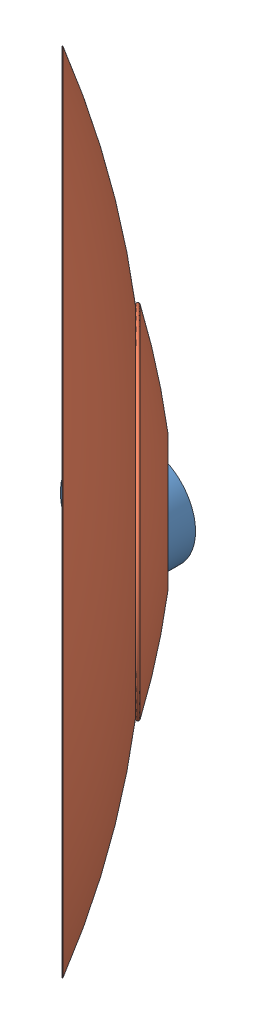
SolidWorks assembly plow disc, configuration Default. Lengths in mm.
Overall size (100.26 128.53 100.26).
2 component instances, 2 part files, 2 mates.
Components (placement in the parent):
- threadnut_seeddrill-1: threadnut_seeddrill [Default] at (3.6245 10.1991 14.902) size (18 18 6)
- FRONTAL BLADE SET-1: FRONTAL BLADE SET [Default] at (-45.3588 10.1991 63.8854) x (0.073204 0.994627 0.073204) z (-0.707107 0 0.707107) size (117.05 117.05 13.26)
Mates (geometry in assembly coordinates):
- Concentric2: concentric: circle of threadnut_seeddrill-1; cylinder of FRONTAL BLADE SET-1 through (3.6245 10.1991 14.902) axis (-0.707107 0 0.707107) radius 10
- Coincident2: coincident: circle of threadnut_seeddrill-1; plane of FRONTAL BLADE SET-1 through (3.6245 10.1991 14.902) normal (-0.707107 0 0.707107)
